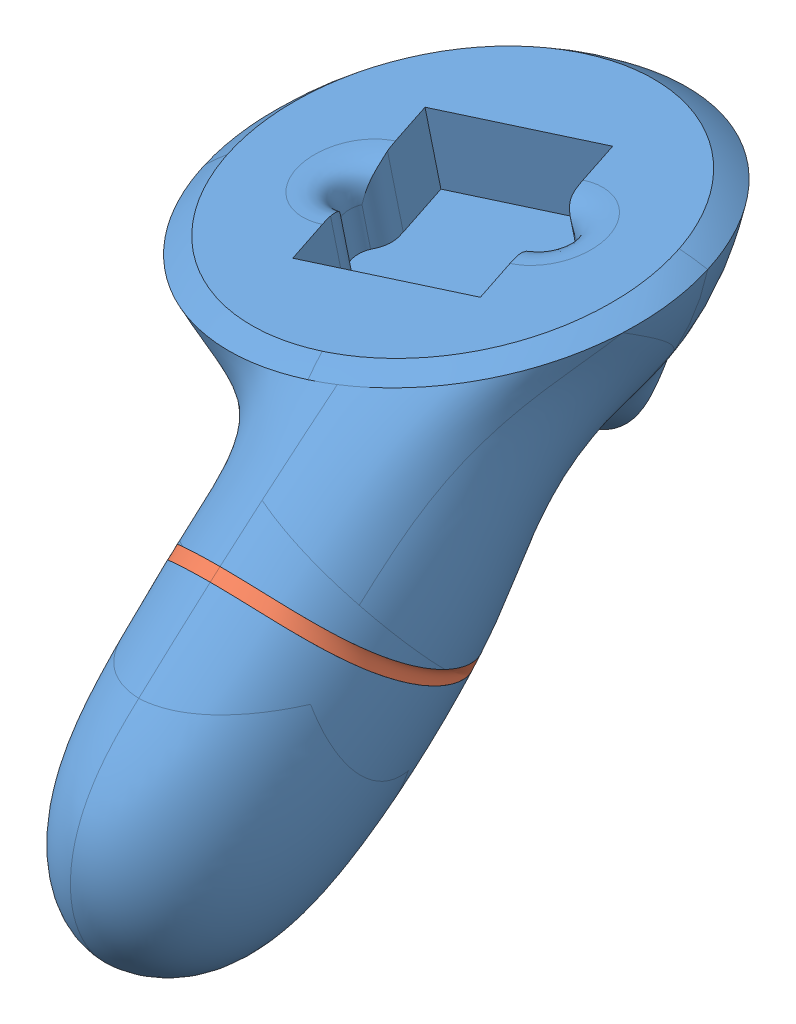
SolidWorks assembly Oculus_Sketch_06_V2, configuration Default. Lengths in mm.
Overall size (63.88 74.1 104.64).
2 component instances, 2 part files, 2 mates.
Components (placement in the parent):
- Touch Exterior SurfacingSK06-Solids-1: Touch Exterior SurfacingSK06-Solids [Default] at (-79.1076 51.2398 9.1378) size (63.88 74.1 104.64)
- Touch Exterior SurfacingSK06-Gummy-1: Touch Exterior SurfacingSK06-Gummy [Default] at (-79.1076 51.2398 9.1378) size (30.22 23.54 36.29)
Mates (geometry in assembly coordinates):
- Parallel1: parallel: face of Touch Exterior SurfacingSK06-Solids-1; face of Touch Exterior SurfacingSK06-Gummy-1
- Coincident1: coincident: point of Touch Exterior SurfacingSK06-Solids-1; point of Touch Exterior SurfacingSK06-Gummy-1
